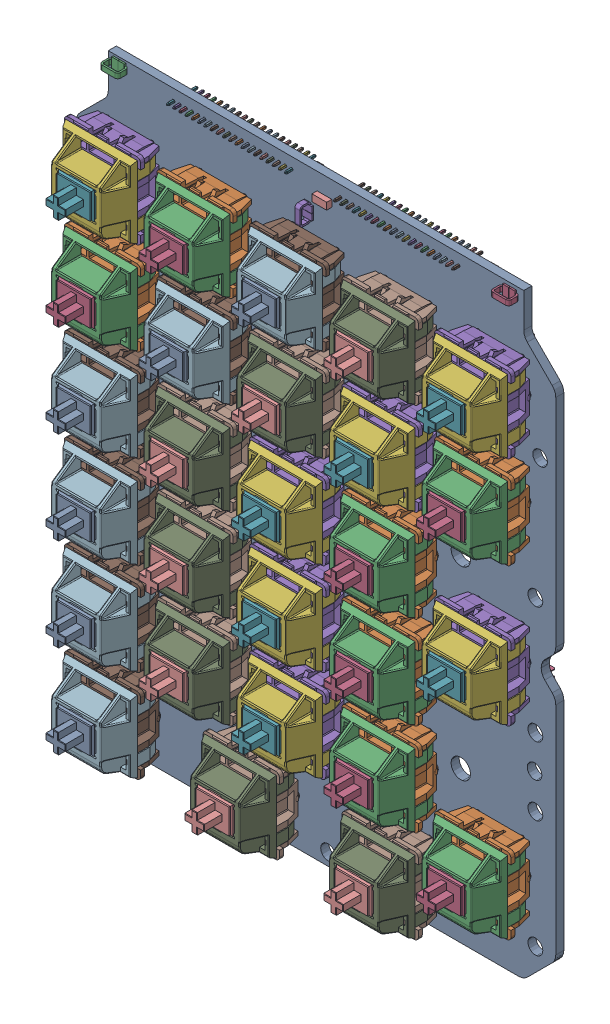
SolidWorks assembly Swithcboard_Calculator, configuration Default. Lengths in mm.
Overall size (98 121.92 20.34).
101 component instances, 12 part files, 0 mates.
Components (placement in the parent):
- Swithcboard_Calculator_BOARD-1: Swithcboard_Calculator_BOARD [Default] at origin size (98 121.92 1.65)
- TC42X-2-101E_TC42X-2-101E-1-1: TC42X-2-101E_TC42X-2-101E-1 [Default] at (59.436 125.476 0.0254) x (0 -1 0) z (0 0 -1) size (2.2 2.8 0.9)
- TC42X-2-101E_TC42X-2-101E-1-2: TC42X-2-101E_TC42X-2-101E-1 [Default] at (17.78 123.19 0.0254) x (0 -1 0) z (0 0 -1) size (2.2 2.8 0.9)
- TC42X-2-101E_TC42X-2-101E-1-3: TC42X-2-101E_TC42X-2-101E-1 [Default] at (98.552 122.809 0.0254) x (0 1 0) z (0 0 -1) size (2.2 2.8 0.9)
- C6749_NPN_BJT_C344010_NCH_MOS-1-1: C6749_NPN_BJT_C344010_NCH_MOS-1 [Default] at (17.399 117.856 0.0254) x (0 -1 0) z (0 0 -1) size (1.4 3 1.05)
- C6749_NPN_BJT_C344010_NCH_MOS-1-2: C6749_NPN_BJT_C344010_NCH_MOS-1 [Default] at (33.782 117.348 0.0254) x (0 -1 0) z (0 0 -1) size (1.4 3 1.05)
- C6749_NPN_BJT_C344010_NCH_MOS-1-3: C6749_NPN_BJT_C344010_NCH_MOS-1 [Default] at (98.425 117.729 0.0254) x (0 -1 0) z (0 0 -1) size (1.4 3 1.05)
- C6749_NPN_BJT_C344010_NCH_MOS-1-4: C6749_NPN_BJT_C344010_NCH_MOS-1 [Default] at (79.629 117.856 0.0254) x (0 -1 0) z (0 0 -1) size (1.4 3 1.05)
- C6749_NPN_BJT_C344010_NCH_MOS-1-5: C6749_NPN_BJT_C344010_NCH_MOS-1 [Default] at (60.706 117.856 0.0254) x (0 -1 0) z (0 0 -1) size (1.4 3 1.05)
- C6749_NPN_BJT_C344010_NCH_MOS-1-6: C6749_NPN_BJT_C344010_NCH_MOS-1 [Default] at (83.312 115.062 0.0254) x (0 -1 0) z (0 0 -1) size (1.4 3 1.05)
- C6749_NPN_BJT_C344010_NCH_MOS-1-7: C6749_NPN_BJT_C344010_NCH_MOS-1 [Default] at (26.416 115.062 0.0254) x (0 -1 0) z (0 0 -1) size (1.4 3 1.05)
- C6749_NPN_BJT_C344010_NCH_MOS-1-8: C6749_NPN_BJT_C344010_NCH_MOS-1 [Default] at (68.199 115.316 0.0254) x (0 -1 0) z (0 0 -1) size (1.4 3 1.05)
- C6749_NPN_BJT_C344010_NCH_MOS-1-9: C6749_NPN_BJT_C344010_NCH_MOS-1 [Default] at (51.435 115.189 0.0254) x (0 -1 0) z (0 0 -1) size (1.4 3 1.05)
- C6749_NPN_BJT_C344010_NCH_MOS-1-10: C6749_NPN_BJT_C344010_NCH_MOS-1 [Default] at (22.86 117.856 0.0254) x (0 -1 0) z (0 0 -1) size (1.4 3 1.05)
- C6749_NPN_BJT_C344010_NCH_MOS-1-11: C6749_NPN_BJT_C344010_NCH_MOS-1 [Default] at (44.069 117.348 0.0254) x (0 -1 0) z (0 0 -1) size (1.4 3 1.05)
- C6749_NPN_BJT_C344010_NCH_MOS-1-12: C6749_NPN_BJT_C344010_NCH_MOS-1 [Default] at (30.099 115.062 0.0254) x (0 -1 0) z (0 0 -1) size (1.4 3 1.05)
- C6749_NPN_BJT_C344010_NCH_MOS-1-13: C6749_NPN_BJT_C344010_NCH_MOS-1 [Default] at (47.752 115.189 0.0254) x (0 -1 0) z (0 0 -1) size (1.4 3 1.05)
- C6749_NPN_BJT_C344010_NCH_MOS-1-14: C6749_NPN_BJT_C344010_NCH_MOS-1 [Default] at (64.389 115.316 0.0254) x (0 -1 0) z (0 0 -1) size (1.4 3 1.05)
- C6749_NPN_BJT_C344010_NCH_MOS-1-15: C6749_NPN_BJT_C344010_NCH_MOS-1 [Default] at (87.122 115.062 0.0254) x (0 -1 0) z (0 0 -1) size (1.4 3 1.05)
- 20_POS_HEADER_20_pos_header-1-1: 20_POS_HEADER_20_pos_header-1 [Default] at (87.0793 125.547 0.0254) x (0 1 0) z (0 0 -1) size (2.1 25.42 6.3)
- 20_POS_HEADER_20_pos_header-1-2: 20_POS_HEADER_20_pos_header-1 [Default] at (52.9493 125.547 0.0254) x (0 1 0) z (0 0 -1) size (2.1 25.42 6.3)
- KSTN-5019_V_CMP-1672-00008-1-1: KSTN-5019_V_CMP-1672-00008-1 [Default] at (17.78 126.365 1.6205) size (3.81 2.03 2.29)
- KSTN-5019_V_CMP-1672-00008-1-2: KSTN-5019_V_CMP-1672-00008-1 [Default] at (97.663 126.111 1.6205) size (3.81 2.03 2.29)
- KSTN-5019_V_CMP-1672-00008-1-3: KSTN-5019_V_CMP-1672-00008-1 [Default] at (56.388 120.015 1.6205) x (0 -1 0) z (0 0 1) size (3.81 2.03 2.29)
- C6749_NPN_BJT_C6749_NPN_BJT-1-1: C6749_NPN_BJT_C6749_NPN_BJT-1 [Default] at (90.617 123.133 0.0254) x (0 -1 0) z (0 0 -1) size (1.4 3 1.05)
- C6749_NPN_BJT_C6749_NPN_BJT-1-2: C6749_NPN_BJT_C6749_NPN_BJT-1 [Default] at (25.654 123.698 0.0254) x (0 -1 0) z (0 0 -1) size (1.4 3 1.05)
- C6749_NPN_BJT_C6749_NPN_BJT-1-3: C6749_NPN_BJT_C6749_NPN_BJT-1 [Default] at (21.971 123.698 0.0254) x (0 1 0) z (0 0 -1) size (1.4 3 1.05)
- C6749_NPN_BJT_C6749_NPN_BJT-1-4: C6749_NPN_BJT_C6749_NPN_BJT-1 [Default] at (94.361 123.133 0.0254) x (0 1 0) z (0 0 -1) size (1.4 3 1.05)
- C6749_NPN_BJT_C6749_NPN_BJT-1-5: C6749_NPN_BJT_C6749_NPN_BJT-1 [Default] at (59.69 123.641 1.6205) x (0 1 0) z (0 0 1) size (1.4 3 1.05)
- C6749_NPN_BJT_C6749_NPN_BJT-1-6: C6749_NPN_BJT_C6749_NPN_BJT-1 [Default] at (56.134 125.349 0.0254) x (-1 0 0) z (0 0 -1) size (1.4 3 1.05)
- J1-0603_Res3-1-1: J1-0603_Res3-1 [Default] at (20.193 121.031 0.0254) x (-1 0 0) z (0 0 -1) size (1.7 0.95 0.9)
- J1-0603_Res3-1-2: J1-0603_Res3-1 [Default] at (22.987 126.238 0.0254) x (1 0 0) z (0 0 -1) size (1.7 0.95 0.9)
- J1-0603_Res3-1-3: J1-0603_Res3-1 [Default] at (91.948 126.492 0.0254) x (-1 0 0) z (0 0 -1) size (1.7 0.95 0.9)
- J1-0603_Res3-1-4: J1-0603_Res3-1 [Default] at (94.361 120.269 0.0254) x (1 0 0) z (0 0 -1) size (1.7 0.95 0.9)
- J1-0603_Res3-1-5: J1-0603_Res3-1 [Default] at (59.817 122.682 0.0254) x (1 0 0) z (0 0 -1) size (1.7 0.95 0.9)
- J1-0603_Res3-1-6: J1-0603_Res3-1 [Default] at (55.372 122.809 0.0254) x (-1 0 0) z (0 0 -1) size (1.7 0.95 0.9)
- J1-0603_Res3-1-7: J1-0603_Res3-1 [Default] at (102.235 27.178 0.0254) x (-1 0 0) z (0 0 -1) size (1.7 0.95 0.9)
- J1-0603_Res3-1-8: J1-0603_Res3-1 [Default] at (86.614 17.653 0.0254) x (0 -1 0) z (0 0 -1) size (1.7 0.95 0.9)
- J1-0603_Res3-1-9: J1-0603_Res3-1 [Default] at (59.944 17.145 0.0254) x (0 -1 0) z (0 0 -1) size (1.7 0.95 0.9)
- J1-0603_Res3-1-10: J1-0603_Res3-1 [Default] at (49.022 32.385 0.0254) x (0 -1 0) z (0 0 -1) size (1.7 0.95 0.9)
- J1-0603_Res3-1-11: J1-0603_Res3-1 [Default] at (31.496 12.319 0.0254) x (0 -1 0) z (0 0 -1) size (1.7 0.95 0.9)
- C6749_NPN_BJT_C15127_PCH_MOS-1-1: C6749_NPN_BJT_C15127_PCH_MOS-1 [Default] at (86.106 24.638 0.0254) x (1 0 0) z (0 0 -1) size (1.4 3 1.05)
- C6749_NPN_BJT_C15127_PCH_MOS-1-2: C6749_NPN_BJT_C15127_PCH_MOS-1 [Default] at (67.437 41.91 0.0254) x (0 -1 0) z (0 0 -1) size (1.4 3 1.05)
- C6749_NPN_BJT_C15127_PCH_MOS-1-3: C6749_NPN_BJT_C15127_PCH_MOS-1 [Default] at (88.265 67.183 0.0254) x (-1 0 0) z (0 0 -1) size (1.4 3 1.05)
- C6749_NPN_BJT_C15127_PCH_MOS-1-4: C6749_NPN_BJT_C15127_PCH_MOS-1 [Default] at (94.996 80.899 0.0254) x (-1 0 0) z (0 0 -1) size (1.4 3 1.05)
- C6749_NPN_BJT_C15127_PCH_MOS-1-5: C6749_NPN_BJT_C15127_PCH_MOS-1 [Default] at (92.964 100.457 0.0254) x (-1 0 0) z (0 0 -1) size (1.4 3 1.05)
- C6749_NPN_BJT_C15127_PCH_MOS-1-6: C6749_NPN_BJT_C15127_PCH_MOS-1 [Default] at (71.755 117.094 0.0254) x (0 -1 0) z (0 0 -1) size (1.4 3 1.05)
- KALIH_HOTSWAP_SMD_STABILIZER_V_Kalih_hotswap_smd-1-1: KALIH_HOTSWAP_SMD_STABILIZER_V_Kalih_hotswap_smd-1 [Default] at (95.7953 24.8128 1.6205) size (15.69 15.6 18.91)
- KALIH_HOTSWAP_SMD_STABILIZER_V_Kalih_hotswap_smd-1-2: KALIH_HOTSWAP_SMD_STABILIZER_V_Kalih_hotswap_smd-1 [Default] at (95.7953 62.6588 1.6205) size (15.69 15.6 18.91)
- KALIH_HOTSWAP_SMD_Kalih_hotswap_smd-1-1: KALIH_HOTSWAP_SMD_Kalih_hotswap_smd-1 [Default] at (76.8723 15.3513 1.6205) size (15.69 15.6 18.91)
- KALIH_HOTSWAP_SMD_Kalih_hotswap_smd-1-2: KALIH_HOTSWAP_SMD_Kalih_hotswap_smd-1 [Default] at (20.1033 15.3513 1.6205) size (15.69 15.6 18.91)
- KALIH_HOTSWAP_SMD_Kalih_hotswap_smd-1-3: KALIH_HOTSWAP_SMD_Kalih_hotswap_smd-1 [Default] at (76.8723 34.2743 1.6205) size (15.69 15.6 18.91)
- KALIH_HOTSWAP_SMD_Kalih_hotswap_smd-1-4: KALIH_HOTSWAP_SMD_Kalih_hotswap_smd-1 [Default] at (57.9493 34.2743 1.6205) size (15.69 15.6 18.91)
- KALIH_HOTSWAP_SMD_Kalih_hotswap_smd-1-5: KALIH_HOTSWAP_SMD_Kalih_hotswap_smd-1 [Default] at (39.0263 34.2743 1.6205) size (15.69 15.6 18.91)
- KALIH_HOTSWAP_SMD_Kalih_hotswap_smd-1-6: KALIH_HOTSWAP_SMD_Kalih_hotswap_smd-1 [Default] at (20.1033 34.2743 1.6205) size (15.69 15.6 18.91)
- KALIH_HOTSWAP_SMD_Kalih_hotswap_smd-1-7: KALIH_HOTSWAP_SMD_Kalih_hotswap_smd-1 [Default] at (76.8723 53.1973 1.6205) size (15.69 15.6 18.91)
- KALIH_HOTSWAP_SMD_Kalih_hotswap_smd-1-8: KALIH_HOTSWAP_SMD_Kalih_hotswap_smd-1 [Default] at (57.9493 53.1973 1.6205) size (15.69 15.6 18.91)
- KALIH_HOTSWAP_SMD_Kalih_hotswap_smd-1-9: KALIH_HOTSWAP_SMD_Kalih_hotswap_smd-1 [Default] at (39.0263 53.1973 1.6205) size (15.69 15.6 18.91)
- KALIH_HOTSWAP_SMD_Kalih_hotswap_smd-1-10: KALIH_HOTSWAP_SMD_Kalih_hotswap_smd-1 [Default] at (20.1033 53.1973 1.6205) size (15.69 15.6 18.91)
- KALIH_HOTSWAP_SMD_Kalih_hotswap_smd-1-11: KALIH_HOTSWAP_SMD_Kalih_hotswap_smd-1 [Default] at (76.8723 72.1203 1.6205) size (15.69 15.6 18.91)
- KALIH_HOTSWAP_SMD_Kalih_hotswap_smd-1-12: KALIH_HOTSWAP_SMD_Kalih_hotswap_smd-1 [Default] at (57.9493 72.1203 1.6205) size (15.69 15.6 18.91)
- KALIH_HOTSWAP_SMD_Kalih_hotswap_smd-1-13: KALIH_HOTSWAP_SMD_Kalih_hotswap_smd-1 [Default] at (39.0263 72.1203 1.6205) size (15.69 15.6 18.91)
- KALIH_HOTSWAP_SMD_Kalih_hotswap_smd-1-14: KALIH_HOTSWAP_SMD_Kalih_hotswap_smd-1 [Default] at (20.1033 72.1203 1.6205) size (15.69 15.6 18.91)
- KALIH_HOTSWAP_SMD_Kalih_hotswap_smd-1-15: KALIH_HOTSWAP_SMD_Kalih_hotswap_smd-1 [Default] at (95.7953 91.0433 1.6205) size (15.69 15.6 18.91)
- KALIH_HOTSWAP_SMD_Kalih_hotswap_smd-1-16: KALIH_HOTSWAP_SMD_Kalih_hotswap_smd-1 [Default] at (76.8723 91.0433 1.6205) size (15.69 15.6 18.91)
- KALIH_HOTSWAP_SMD_Kalih_hotswap_smd-1-17: KALIH_HOTSWAP_SMD_Kalih_hotswap_smd-1 [Default] at (57.9493 91.0433 1.6205) size (15.69 15.6 18.91)
- KALIH_HOTSWAP_SMD_Kalih_hotswap_smd-1-18: KALIH_HOTSWAP_SMD_Kalih_hotswap_smd-1 [Default] at (39.0263 91.0433 1.6205) size (15.69 15.6 18.91)
- KALIH_HOTSWAP_SMD_Kalih_hotswap_smd-1-19: KALIH_HOTSWAP_SMD_Kalih_hotswap_smd-1 [Default] at (20.1033 91.0433 1.6205) size (15.69 15.6 18.91)
- KALIH_HOTSWAP_SMD_Kalih_hotswap_smd-1-20: KALIH_HOTSWAP_SMD_Kalih_hotswap_smd-1 [Default] at (95.7953 109.9663 1.6205) size (15.69 15.6 18.91)
- KALIH_HOTSWAP_SMD_Kalih_hotswap_smd-1-21: KALIH_HOTSWAP_SMD_Kalih_hotswap_smd-1 [Default] at (76.8723 109.9663 1.6205) size (15.69 15.6 18.91)
- KALIH_HOTSWAP_SMD_Kalih_hotswap_smd-1-22: KALIH_HOTSWAP_SMD_Kalih_hotswap_smd-1 [Default] at (57.9493 109.9663 1.6205) size (15.69 15.6 18.91)
- KALIH_HOTSWAP_SMD_Kalih_hotswap_smd-1-23: KALIH_HOTSWAP_SMD_Kalih_hotswap_smd-1 [Default] at (39.0263 109.9663 1.6205) size (15.69 15.6 18.91)
- KALIH_HOTSWAP_SMD_Kalih_hotswap_smd-1-24: KALIH_HOTSWAP_SMD_Kalih_hotswap_smd-1 [Default] at (20.1033 109.9663 1.6205) size (15.69 15.6 18.91)
- KALIH_HOTSWAP_SMD_STABILIZER_H_Kalih_hotswap_smd-1-1: KALIH_HOTSWAP_SMD_STABILIZER_H_Kalih_hotswap_smd-1 [Default] at (48.4878 15.3513 1.6205) size (15.69 15.6 18.91)
- C2128_SOD323_C2128_Diode-1-1: C2128_SOD323_C2128_Diode-1 [Default] at (104.648 26.035 0.0254) x (0 -1 0) z (0 0 -1) size (1.8 1.4 1.1)
- C2128_SOD323_C2128_Diode-1-2: C2128_SOD323_C2128_Diode-1 [Default] at (84.582 17.526 0.0254) x (0 -1 0) z (0 0 -1) size (1.8 1.4 1.1)
- C2128_SOD323_C2128_Diode-1-3: C2128_SOD323_C2128_Diode-1 [Default] at (57.785 16.764 0.0254) x (0 -1 0) z (0 0 -1) size (1.8 1.4 1.1)
- C2128_SOD323_C2128_Diode-1-4: C2128_SOD323_C2128_Diode-1 [Default] at (29.337 16.764 0.0254) x (0 -1 0) z (0 0 -1) size (1.8 1.4 1.1)
- C2128_SOD323_C2128_Diode-1-5: C2128_SOD323_C2128_Diode-1 [Default] at (79.629 24.892 0.0254) x (1 0 0) z (0 0 -1) size (1.8 1.4 1.1)
- C2128_SOD323_C2128_Diode-1-6: C2128_SOD323_C2128_Diode-1 [Default] at (67.31 35.306 0.0254) x (0 -1 0) z (0 0 -1) size (1.8 1.4 1.1)
- C2128_SOD323_C2128_Diode-1-7: C2128_SOD323_C2128_Diode-1 [Default] at (48.006 36.068 0.0254) x (0 -1 0) z (0 0 -1) size (1.8 1.4 1.1)
- C2128_SOD323_C2128_Diode-1-8: C2128_SOD323_C2128_Diode-1 [Default] at (29.464 35.687 0.0254) x (0 -1 0) z (0 0 -1) size (1.8 1.4 1.1)
- C2128_SOD323_C2128_Diode-1-9: C2128_SOD323_C2128_Diode-1 [Default] at (103.251 67.691 0.0254) x (0 -1 0) z (0 0 -1) size (1.8 1.4 1.1)
- C2128_SOD323_C2128_Diode-1-10: C2128_SOD323_C2128_Diode-1 [Default] at (85.852 57.531 0.0254) x (0 -1 0) z (0 0 -1) size (1.8 1.4 1.1)
- C2128_SOD323_C2128_Diode-1-11: C2128_SOD323_C2128_Diode-1 [Default] at (67.437 54.483 0.0254) x (0 -1 0) z (0 0 -1) size (1.8 1.4 1.1)
- C2128_SOD323_C2128_Diode-1-12: C2128_SOD323_C2128_Diode-1 [Default] at (48.387 54.356 0.0254) x (0 -1 0) z (0 0 -1) size (1.8 1.4 1.1)
- C2128_SOD323_C2128_Diode-1-13: C2128_SOD323_C2128_Diode-1 [Default] at (29.591 54.483 0.0254) x (0 -1 0) z (0 0 -1) size (1.8 1.4 1.1)
- C2128_SOD323_C2128_Diode-1-14: C2128_SOD323_C2128_Diode-1 [Default] at (84.328 80.264 0.0254) x (0 -1 0) z (0 0 -1) size (1.8 1.4 1.1)
- C2128_SOD323_C2128_Diode-1-15: C2128_SOD323_C2128_Diode-1 [Default] at (67.437 74.041 0.0254) x (0 -1 0) z (0 0 -1) size (1.8 1.4 1.1)
- C2128_SOD323_C2128_Diode-1-16: C2128_SOD323_C2128_Diode-1 [Default] at (48.387 73.914 0.0254) x (0 -1 0) z (0 0 -1) size (1.8 1.4 1.1)
- C2128_SOD323_C2128_Diode-1-17: C2128_SOD323_C2128_Diode-1 [Default] at (29.591 73.914 0.0254) x (0 -1 0) z (0 0 -1) size (1.8 1.4 1.1)
- C2128_SOD323_C2128_Diode-1-18: C2128_SOD323_C2128_Diode-1 [Default] at (103.378 93.218 0.0254) x (0 -1 0) z (0 0 -1) size (1.8 1.4 1.1)
- C2128_SOD323_C2128_Diode-1-19: C2128_SOD323_C2128_Diode-1 [Default] at (86.233 92.964 0.0254) x (0 -1 0) z (0 0 -1) size (1.8 1.4 1.1)
- C2128_SOD323_C2128_Diode-1-20: C2128_SOD323_C2128_Diode-1 [Default] at (67.31 93.091 0.0254) x (0 -1 0) z (0 0 -1) size (1.8 1.4 1.1)
- C2128_SOD323_C2128_Diode-1-21: C2128_SOD323_C2128_Diode-1 [Default] at (48.387 93.218 0.0254) x (0 -1 0) z (0 0 -1) size (1.8 1.4 1.1)
- C2128_SOD323_C2128_Diode-1-22: C2128_SOD323_C2128_Diode-1 [Default] at (29.591 93.218 0.0254) x (0 -1 0) z (0 0 -1) size (1.8 1.4 1.1)
- C2128_SOD323_C2128_Diode-1-23: C2128_SOD323_C2128_Diode-1 [Default] at (103.505 111.252 0.0254) x (0 -1 0) z (0 0 -1) size (1.8 1.4 1.1)
- C2128_SOD323_C2128_Diode-1-24: C2128_SOD323_C2128_Diode-1 [Default] at (86.868 110.617 0.0254) x (0 -1 0) z (0 0 -1) size (1.8 1.4 1.1)
- C2128_SOD323_C2128_Diode-1-25: C2128_SOD323_C2128_Diode-1 [Default] at (67.945 110.744 0.0254) x (0 -1 0) z (0 0 -1) size (1.8 1.4 1.1)
- C2128_SOD323_C2128_Diode-1-26: C2128_SOD323_C2128_Diode-1 [Default] at (49.022 110.744 0.0254) x (0 -1 0) z (0 0 -1) size (1.8 1.4 1.1)
- C2128_SOD323_C2128_Diode-1-27: C2128_SOD323_C2128_Diode-1 [Default] at (30.099 110.871 0.0254) x (0 -1 0) z (0 0 -1) size (1.8 1.4 1.1)
